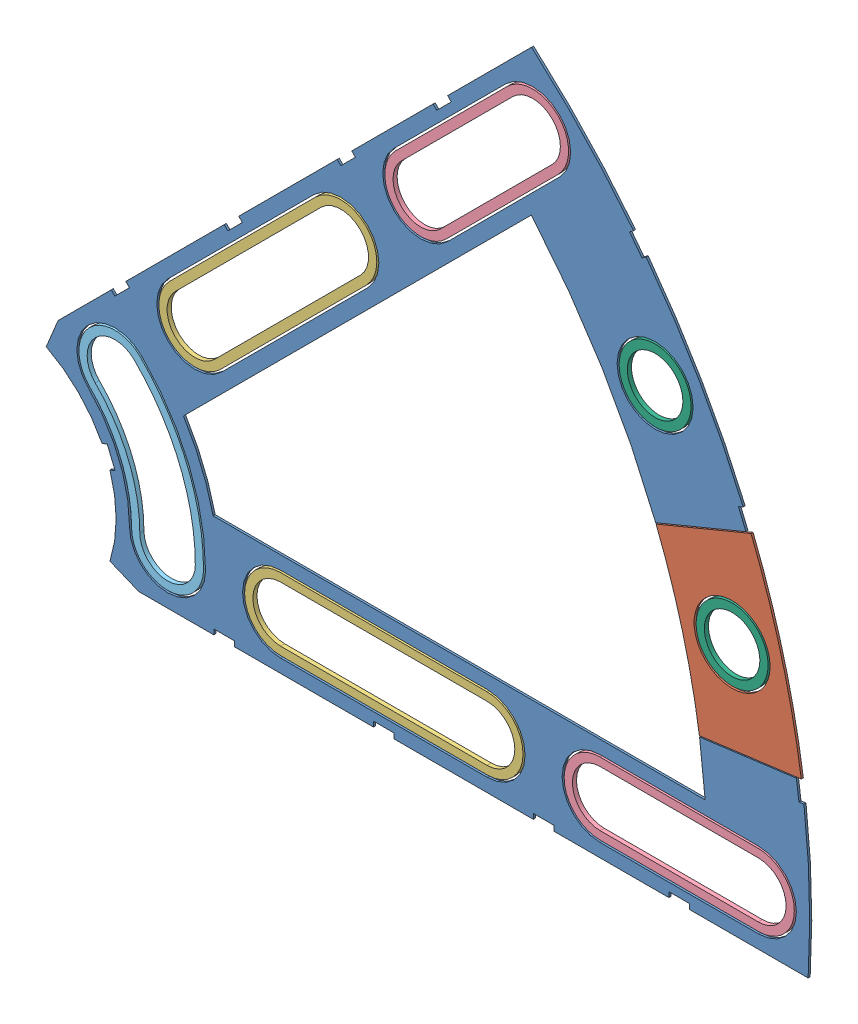
SolidWorks assembly Clover_7_Insul+Pass, configuration Default. Lengths in mm.
Overall size (96.77 82.54 0.51).
9 component instances, 6 part files, 22 mates.
Components (placement in the parent):
- Clover_7_Insul-1: Clover_7_Insul [Default] at (-27.6058 15.254 76.1229) size (94.37 82.54 0.25)
- Clover_7_Pass-1: Clover_7_Pass [Default] at (-27.6058 15.254 76.1229) size (17.95 24.84 0.25)
- Clover_Long_Washer-1: Clover_Long_Washer [Default] at (7.0131 49.8729 76.3769) x (0.707107 0.707107 0) z (-0.707107 0.707107 0) size (34.42 0.51 8.89)
- Clover_Long_Washer-2: Clover_Long_Washer [Default] at (21.3527 15.254 76.3769) x (1 0 0) z (0 1 0) size (34.42 0.51 8.89)
- Clover_Med_Washer-1: Clover_Med_Washer [Default] at (32.8313 75.6911 76.3769) x (0.707107 0.707107 0) z (-0.707107 0.707107 0) size (28.45 0.51 8.89)
- Clover_Med_Washer-2: Clover_Med_Washer [Default] at (57.8652 15.254 76.3769) x (1 0 0) z (0 1 0) size (28.45 0.51 8.89)
- Curve_Inner_Washer-1: Curve_Inner_Washer [Default] at (-27.6058 15.254 76.3769) x (0.707107 0.707107 0) z (-0.707107 0.707107 0) size (15.4 0.51 24.61)
- Round_Washer-1: Round_Washer [Default] at (54.8831 62.879 76.3769) x (1 0 0) z (0 1 0) size (8.89 0.51 8.89)
- Round_Washer-2: Round_Washer [Default] at (64.3986 39.9065 76.3769) x (1 0 0) z (0 1 0) size (8.89 0.51 8.89)
Mates (geometry in assembly coordinates):
- Coincident1: coincident: plane of Clover_7_Insul-1 through (-27.6058 15.254 76.3769) normal (0 0 1); plane of Clover_7_Pass-1 through (-27.6058 15.254 76.3769) normal (0 0 1)
- Concentric1: concentric: cylinder of Clover_7_Insul-1 through (-27.6058 15.254 76.3769) axis (0 0 -1) radius 101.6; cylinder of Clover_7_Pass-1 through (-27.6058 15.254 76.3769) axis (0 0 -1) radius 101.6
- Parallel1: parallel: plane of Clover_7_Insul-1 through (53.7843 47.7297 76.1229) normal (0.382683 -0.92388 0); plane of Clover_7_Pass-1 through (66.1597 52.7183 76.1229) normal (-0.382683 0.92388 0)
- Concentric2: concentric: circle of Clover_7_Pass-1; circle of Round_Washer-2
- Coincident2: coincident: plane of Clover_7_Pass-1 through (-27.6058 15.254 76.3769) normal (0 0 1); plane of Round_Washer-2 through (64.3986 39.9065 76.3769) normal (0 0 1)
- Concentric3: concentric: circle of Clover_7_Insul-1; circle of Round_Washer-1
- Coincident3: coincident: plane of Clover_7_Insul-1 through (-27.6058 15.254 76.3769) normal (0 0 1); plane of Round_Washer-1 through (54.8831 62.879 76.3769) normal (0 0 1)
- Concentric4: concentric: circle of Clover_7_Insul-1; circle of Clover_Med_Washer-1
- Concentric5: concentric: circle of Clover_7_Insul-1; circle of Clover_Med_Washer-1
- Coincident4: coincident: plane of Clover_7_Insul-1 through (-27.6058 15.254 76.3769) normal (0 0 1); plane of Clover_Med_Washer-1 through (25.9165 68.7763 76.3769) normal (0 0 1)
- Concentric6: concentric: circle of Clover_7_Insul-1; circle of Clover_Long_Washer-1
- Concentric7: concentric: circle of Clover_7_Insul-1; circle of Clover_Long_Washer-1
- Coincident5: coincident: plane of Clover_7_Insul-1 through (-27.6058 15.254 76.3769) normal (0 0 1); plane of Clover_Long_Washer-1 through (-2.0121 40.8478 76.3769) normal (0 0 1)
- Concentric8: concentric: circle of Clover_7_Insul-1; circle of Curve_Inner_Washer-1
- Concentric9: concentric: circle of Clover_7_Insul-1; circle of Curve_Inner_Washer-1
- Coincident6: coincident: plane of Clover_7_Insul-1 through (-27.6058 15.254 76.3769) normal (0 0 1); plane of Curve_Inner_Washer-1 through (-19.7481 23.1117 76.3769) normal (0 0 1)
- Concentric10: concentric: circle of Clover_7_Insul-1; circle of Clover_Long_Washer-2
- Concentric11: concentric: circle of Clover_7_Insul-1; circle of Clover_Long_Washer-2
- Coincident7: coincident: plane of Clover_7_Insul-1 through (-27.6058 15.254 76.3769) normal (0 0 1); plane of Clover_Long_Washer-2 through (8.5892 15.254 76.3769) normal (0 0 1)
- Concentric12: concentric: circle of Clover_7_Insul-1; circle of Clover_Med_Washer-2
- Concentric13: concentric: circle of Clover_7_Insul-1; circle of Clover_Med_Washer-2
- Coincident8: coincident: plane of Clover_7_Insul-1 through (-27.6058 15.254 76.3769) normal (0 0 1); plane of Clover_Med_Washer-2 through (48.0862 15.254 76.3769) normal (0 0 1)
